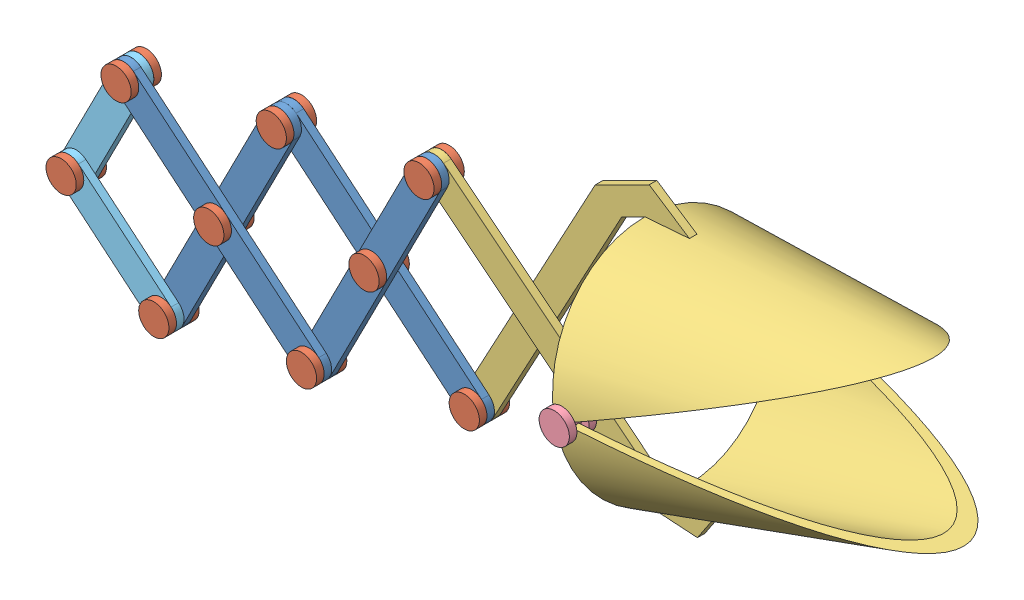
SolidWorks assembly Extendable Arm, configuration Default. Lengths in mm.
Overall size (380.86 173.26 101.48).
19 component instances, 5 part files, 40 mates.
Components (placement in the parent):
- Bar for Arm-1: Bar for Arm [Default] at (-4.1157 50.0758 -3.441) x (0.76675 -0.641946 0) z (0 0 1) size (114.3 12.7 3.17)
- Bar for Arm-2: Bar for Arm [Default] at (119.9749 75.348 -6.616) x (-0.454614 -0.890688 0) z (0 0 1) size (114.3 12.7 3.17)
- Bar for Arm-3: Bar for Arm [Default] at (57.9296 62.7119 -6.616) x (-0.454614 -0.890688 0) z (0 0 1) size (114.3 12.7 3.17)
- Bar for Arm-4: Bar for Arm [Default] at (57.9296 62.7119 -9.791) x (0.76675 -0.641946 0) z (0 0 1) size (114.3 12.7 3.17)
- Bar Link-1: Bar Link [Default] at (34.8352 17.465 -9.791) x (0.155574 -0.987824 0) z (0 0 1) size (12.7 12.7 12.7)
- Bar Link-2: Bar Link [Default] at (96.8805 30.1011 -12.966) size (12.7 12.7 12.7)
- Bar Link-3: Bar Link [Default] at (57.9296 62.7119 -12.966) x (-0.730761 0.682634 0) z (0 0 1) size (12.7 12.7 12.7)
- Bar Link-4: Bar Link [Default] at (73.7861 -15.1459 -9.791) size (12.7 12.7 12.7)
- Claw 3-1: Claw 3 [Default] at (214.8539 54.9746 -9.791) x (-0.192507 0.981296 0) z (0 0 1) size (104.15 216.18 95.42)
- Claw 3-2: Claw 3 [Default] at (215.1852 53.3478 -9.791) x (0.206609 -0.978424 0) z (0 0 -1) size (104.15 216.18 95.42)
- Claw Pin 2-1: Claw Pin 2 [Default] at (218.0225 54.7728 32.6956) x (0.990389 0.138308 0) z (0 0 1) size (12.7 12.7 11.43)
- Claw Pin 2-2: Claw Pin 2 [Default] at (218.0225 54.7728 -57.3576) x (0.99994 0.010984 0) z (0 0 1) size (12.7 12.7 11.43)
- Bar Link-5: Bar Link [Default] at (135.8314 -2.5098 -16.141) size (12.7 12.7 12.7)
- Bar Link-6: Bar Link [Default] at (119.9749 75.348 -12.966) size (12.7 12.7 12.7)
- Bar for Arm 2-3: Bar for Arm 2 [Default] at (-27.2101 4.8288 -3.441) x (0.76675 -0.641946 0) z (0 0 1) size (63.5 12.7 3.17)
- Bar for Arm 2-4: Bar for Arm 2 [Default] at (-27.2101 4.8288 -6.616) x (0.454614 0.890688 0) z (0 0 1) size (63.5 12.7 3.17)
- Bar Link-7: Bar Link [Default] at (-4.1157 50.0758 -9.791) size (12.7 12.7 12.7)
- Bar Link-8: Bar Link [Default] at (11.7408 -27.782 -9.791) size (12.7 12.7 12.7)
- Bar Link-9: Bar Link [Default] at (-27.2101 4.8288 -9.791) x (-0.137927 -0.990442 0) z (0 0 1) size (12.7 12.7 12.7)
Mates (geometry in assembly coordinates):
- Coincident11: coincident anti-aligned: plane of Bar for Arm-1 through (-4.1157 50.0758 -3.441) normal (0 0 -1); plane of Bar for Arm-2 through (119.9749 75.348 -3.441) normal (0 0 1)
- Concentric13: concentric aligned: cylinder of Bar for Arm-1 through (73.7861 -15.1459 -0.266) axis (0 0 -1) radius 3.175; cylinder of Bar for Arm-2 through (73.7861 -15.1459 -3.441) axis (0 0 -1) radius 3.175
- Coincident12: coincident anti-aligned: plane of Bar for Arm-2 through (119.9749 75.348 -6.616) normal (0 0 -1); plane of Bar for Arm-4 through (57.9296 62.7119 -6.616) normal (0 0 1)
- Coincident13: coincident anti-aligned: plane of Bar for Arm-1 through (-4.1157 50.0758 -3.441) normal (0 0 -1); plane of Bar for Arm-3 through (57.9296 62.7119 -3.441) normal (0 0 1)
- Concentric15: concentric aligned: cylinder of Bar for Arm-1 through (34.8352 17.465 -0.266) axis (0 0 -1) radius 3.175; cylinder of Bar for Arm-3 through (34.8352 17.465 -3.441) axis (0 0 -1) radius 3.175
- Concentric16: concentric aligned: cylinder of Bar for Arm-3 through (57.9296 62.7119 -3.441) axis (0 0 -1) radius 3.175; cylinder of Bar for Arm-4 through (57.9296 62.7119 -6.616) axis (0 0 -1) radius 3.175
- Concentric17: concentric aligned: cylinder of Bar for Arm-2 through (96.8805 30.1011 -3.441) axis (0 0 -1) radius 3.175; cylinder of Bar for Arm-4 through (96.8805 30.1011 -6.616) axis (0 0 -1) radius 3.175
- Concentric18: concentric aligned: cylinder of Bar for Arm-2 through (96.8805 30.1011 -3.441) axis (0 0 -1) radius 3.175; cylinder of Bar Link-2 through (96.8805 30.1011 -3.441) axis (0 0 -1) radius 3.175
- Coincident14: coincident anti-aligned: plane of Bar for Arm-2 through (119.9749 75.348 -3.441) normal (0 0 1); plane of Bar Link-2 through (96.8805 30.1011 -3.441) normal (0 0 -1)
- Concentric19: concentric aligned: cylinder of Bar for Arm-3 through (34.8352 17.465 -3.441) axis (0 0 -1) radius 3.175; cylinder of Bar Link-1 through (34.8352 17.465 -0.266) axis (0 0 -1) radius 3.175
- Coincident15: coincident anti-aligned: plane of Bar for Arm-3 through (57.9296 62.7119 -6.616) normal (0 0 -1); plane of Bar Link-1 through (34.8352 17.465 -6.616) normal (0 0 1)
- Concentric20: concentric aligned: cylinder of Bar for Arm-1 through (73.7861 -15.1459 -0.266) axis (0 0 -1) radius 3.175; cylinder of Bar Link-4 through (73.7861 -15.1459 -0.266) axis (0 0 -1) radius 3.175
- Coincident17: coincident anti-aligned: plane of Bar for Arm-2 through (119.9749 75.348 -6.616) normal (0 0 -1); plane of Bar Link-4 through (73.7861 -15.1459 -6.616) normal (0 0 1)
- Concentric21: concentric aligned: cylinder of Bar for Arm-3 through (57.9296 62.7119 -3.441) axis (0 0 -1) radius 3.175; cylinder of Bar Link-3 through (57.9296 62.7119 -3.441) axis (0 0 -1) radius 3.175
- Coincident18: coincident anti-aligned: plane of Bar for Arm-4 through (57.9296 62.7119 -9.791) normal (0 0 -1); plane of Bar Link-3 through (57.9296 62.7119 -9.791) normal (0 0 1)
- Concentric22: concentric anti-aligned: cylinder of Claw 3-1 through (218.0225 54.7728 -57.416) axis (0 0 1) radius 3.175; cylinder of Claw Pin 2-1 through (218.0225 54.7728 37.7756) axis (0 0 -1) radius 3.175
- Coincident19: coincident: point of Claw 3-1; plane of Claw Pin 2-1 through (218.0225 54.7728 37.7756) normal (0 0 -1)
- Concentric23: concentric anti-aligned: cylinder of Claw 3-1 through (218.0225 54.7728 -57.416) axis (0 0 1) radius 3.175; cylinder of Claw Pin 2-2 through (218.0225 54.7728 -52.2776) axis (0 0 -1) radius 3.175
- Coincident20: coincident: point of Claw 3-1; plane of Claw Pin 2-2 through (218.0225 54.7728 -57.3576) normal (0 0 1)
- Concentric24: concentric aligned: cylinder of Claw 3-2 through (218.0225 54.7728 37.834) axis (0 0 -1) radius 3.175; cylinder of Claw Pin 2-2 through (218.0225 54.7728 -52.2776) axis (0 0 -1) radius 3.175
- Coincident21: coincident: point of Claw 3-2; plane of Claw Pin 2-2 through (218.0225 54.7728 -57.3576) normal (0 0 1)
- Coincident22: coincident: point of Claw 3-2; plane of Claw Pin 2-1 through (218.0225 54.7728 37.7756) normal (0 0 -1)
- Coincident26: coincident anti-aligned: plane of Bar for Arm-4 through (57.9296 62.7119 -9.791) normal (0 0 -1); plane of Claw 3-2 through (135.8314 -2.5098 -9.791) normal (0 0 1)
- Concentric32: concentric anti-aligned: cylinder of Bar for Arm-4 through (135.8314 -2.5098 -6.616) axis (0 0 -1) radius 3.175; cylinder of Claw 3-2 through (135.8314 -2.5098 -12.966) axis (0 0 1) radius 3.175
- Concentric33: concentric aligned: cylinder of Bar for Arm-2 through (119.9749 75.348 -3.441) axis (0 0 -1) radius 3.175; cylinder of Claw 3-1 through (119.9749 75.348 -6.616) axis (0 0 -1) radius 3.175
- Concentric34: concentric anti-aligned: cylinder of Claw 3-2 through (135.8314 -2.5098 -12.966) axis (0 0 1) radius 3.175; cylinder of Bar Link-5 through (135.8314 -2.5098 -6.616) axis (0 0 -1) radius 3.175
- Coincident27: coincident anti-aligned: plane of Claw 3-2 through (135.8314 -2.5098 -12.966) normal (0 0 -1); plane of Bar Link-5 through (135.8314 -2.5098 -12.966) normal (0 0 1)
- Concentric35: concentric aligned: cylinder of Claw 3-1 through (119.9749 75.348 -6.616) axis (0 0 -1) radius 3.175; cylinder of Bar Link-6 through (119.9749 75.348 -3.441) axis (0 0 -1) radius 3.175
- Coincident28: coincident anti-aligned: plane of Claw 3-1 through (119.9749 75.348 -9.791) normal (0 0 -1); plane of Bar Link-6 through (119.9749 75.348 -9.791) normal (0 0 1)
- Coincident29: coincident anti-aligned: plane of Bar for Arm-3 through (57.9296 62.7119 -3.441) normal (0 0 1); plane of Bar for Arm 2-3 through (-27.2101 4.8288 -3.441) normal (0 0 -1)
- Concentric36: concentric aligned: cylinder of Bar for Arm-3 through (11.7408 -27.782 -3.441) axis (0 0 -1) radius 3.175; cylinder of Bar for Arm 2-3 through (11.7408 -27.782 -0.266) axis (0 0 -1) radius 3.175
- Coincident30: coincident anti-aligned: plane of Bar for Arm-1 through (-4.1157 50.0758 -3.441) normal (0 0 -1); plane of Bar for Arm 2-4 through (-27.2101 4.8288 -3.441) normal (0 0 1)
- Concentric37: concentric aligned: cylinder of Bar for Arm-1 through (-4.1157 50.0758 -0.266) axis (0 0 -1) radius 3.175; cylinder of Bar for Arm 2-4 through (-4.1157 50.0758 -3.441) axis (0 0 -1) radius 3.175
- Concentric38: concentric aligned: cylinder of Bar for Arm 2-3 through (-27.2101 4.8288 -0.266) axis (0 0 -1) radius 3.175; cylinder of Bar for Arm 2-4 through (-27.2101 4.8288 -3.441) axis (0 0 -1) radius 3.175
- Concentric39: concentric aligned: cylinder of Bar for Arm-3 through (11.7408 -27.782 -3.441) axis (0 0 -1) radius 3.175; cylinder of Bar Link-8 through (11.7408 -27.782 -0.266) axis (0 0 -1) radius 3.175
- Coincident31: coincident anti-aligned: plane of Bar for Arm 2-3 through (-27.2101 4.8288 -0.266) normal (0 0 1); plane of Bar Link-8 through (11.7408 -27.782 -0.266) normal (0 0 -1)
- Concentric40: concentric aligned: cylinder of Bar for Arm 2-4 through (-4.1157 50.0758 -3.441) axis (0 0 -1) radius 3.175; cylinder of Bar Link-7 through (-4.1157 50.0758 -0.266) axis (0 0 -1) radius 3.175
- Coincident32: coincident anti-aligned: plane of Bar for Arm-1 through (-4.1157 50.0758 -0.266) normal (0 0 1); plane of Bar Link-7 through (-4.1157 50.0758 -0.266) normal (0 0 -1)
- Concentric41: concentric aligned: cylinder of Bar for Arm 2-4 through (-27.2101 4.8288 -3.441) axis (0 0 -1) radius 3.175; cylinder of Bar Link-9 through (-27.2101 4.8288 -0.266) axis (0 0 -1) radius 3.175
- Coincident33: coincident anti-aligned: plane of Bar for Arm 2-3 through (-27.2101 4.8288 -0.266) normal (0 0 1); plane of Bar Link-9 through (-27.2101 4.8288 -0.266) normal (0 0 -1)
